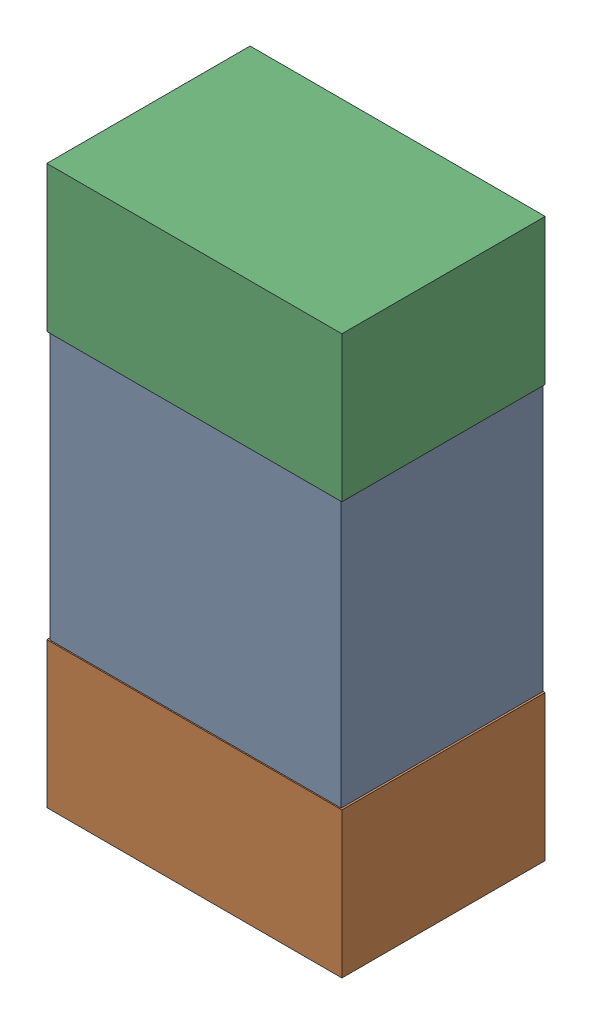
SolidWorks assembly CoutMByp2Kanaloa_v2.0.0_Power, configuration Default. Lengths in mm.
Overall size (1.83 3.45 1.26).
6 component instances, 2 part files, 0 mates.
Components (placement in the parent):
- 378154176-1: 378154176 [Default] at (57.05 49.925 0) size (1.8 3.4 1.25)
  - Extruded_12-1: Extruded_12 [Default] at origin size (1.8 3.4 1.25)
- 378154304-1: 378154304 [Default] at (57.05 48.65 0) size (1.83 0.9 1.26)
  - Extruded_13-1: Extruded_13 [Default] at origin size (1.83 0.9 1.26)
- 378154304-2: 378154304 [Default] at (57.05 51.2 0) size (1.83 0.9 1.26)
  - Extruded_13-1: Extruded_13 [Default] at origin size (1.83 0.9 1.26)
